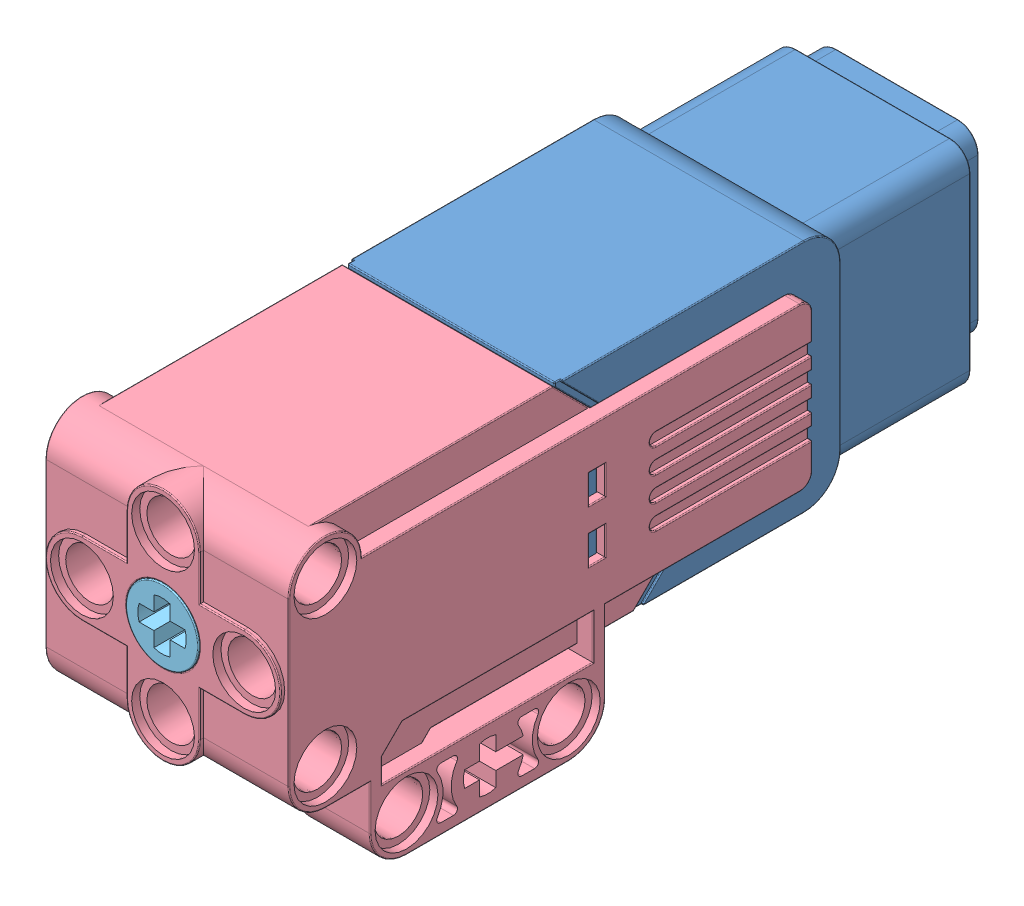
SolidWorks assembly EV3 Medium Servo Motor , configuration Default. Lengths in mm.
Overall size (24 31.22 72.5).
7 component instances, 5 part files, 0 mates.
Components (placement in the parent):
- 99455.stp-1: 99455.stp [Default] at origin size (24 31.22 72.5)
  - 99535c01.stp-1: 99535c01.stp [Default] at origin size (24 31.22 72.4)
    - 99534-White.stp-1: 99534-White.stp [Default] at origin size (22.4 23.2 44.8)
    - 54732b-LtBluishGray.stp-1: 54732b-LtBluishGray.stp [Default] at (0 0.8 -16) x (-1 0 0) z (0 0 -1) size (12 14.56 14.4)
    - 99542-MilkyWhite.stp-1: 99542-MilkyWhite.stp [Default] at (0 0 48.4) x (1 0 0) z (0 0 -1) size (20.8 20.8 2.4)
    - 99535-LtBluishGray.stp-1: 99535-LtBluishGray.stp [Default] at (0 0 28.4) size (24 31.22 52)
  - 99543-Red.stp-1: 99543-Red.stp [Default] at (0 0 47.7) size (16 16 12.4)
